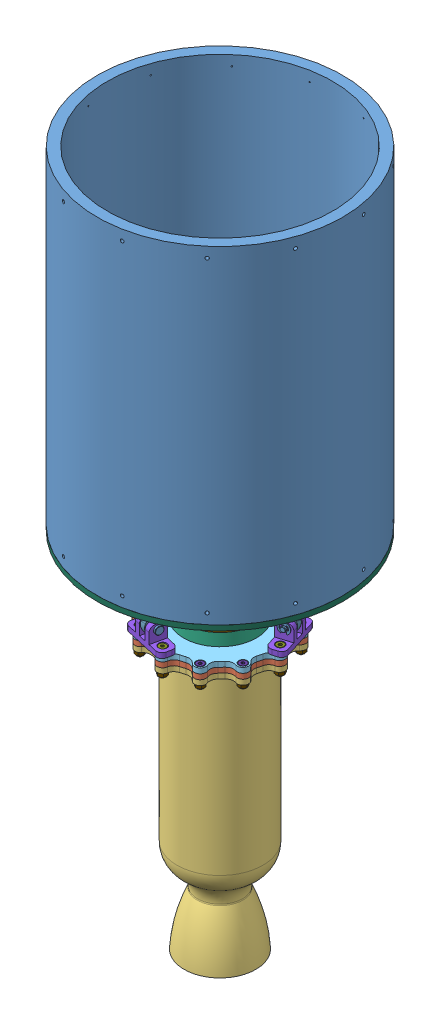
SolidWorks assembly 000067-R01_ENGINE_ASSM, configuration Default. Lengths in mm.
Overall size (591.83 861.8 591.83).
60 component instances, 19 part files, 17 mates.
Components (placement in the parent):
- 000057-R01_FIN_CAN_TUBE_ASSM-1: 000057-R01_FIN_CAN_TUBE_ASSM [Default] at (22.2086 29.6908 -254.9462) x (0.98247 0 -0.186422) z (0.186422 0 0.98247) size (304.8 406.4 304.8)
  - 000070-R01_FIN_CAN_AF-1: 000070-R01_FIN_CAN_AF [Default] at (6.0261 200.1811 396.9011) size (304.8 406.4 304.8)
- 000014-R02_REMOVE_BEFORE_FLIGHT_ASSM-1: 000014-R02_REMOVE_BEFORE_FLIGHT_ASSM [Default] at (94.6044 -143.2219 138.4138) x (-0.855947 0 0.517064) z (-0.517064 0 -0.855947) size (431.04 487.19 431.04)
  - 000030-R02_FILM_COOLING_VOLUTE-2: 000030-R02_FILM_COOLING_VOLUTE [Default] at (-8.7806 254.8412 0) x (-0.965926 0 -0.258819) z (0.258819 0 -0.965926) size (156.79 34.88 257.08)
  - 000001-R05_RBF_TCA-2: 000001-R05_RBF_TCA [Default] at (-8.7806 -14.701 0) x (0 -1 0) z (0 0 1) size (343.5 185.64 158.75)
  - 000015-R05_PINTLE_INJECT_ASSM-1: 000015-R05_PINTLE_INJECT_ASSM [Default] at (86.4435 164.1172 71.5928) x (-0.866025 0 0.5) z (-0.5 0 -0.866025) size (158.75 36.86 158.75)
    - 000033-R01_PINTLE_BOTTOM_PLATE-1: 000033-R01_PINTLE_BOTTOM_PLATE [Default] at (46.67 88.1839 109.6132) size (87.7 15.24 87.7)
    - 000032-R02_PINTLE_MIDDLE_PLATE-1: 000032-R02_PINTLE_MIDDLE_PLATE [Default] at (46.67 92.7382 109.6132) size (158.75 29.57 158.75)
    - 000031-R01_PINTLE_UPPER_PLATE-1: 000031-R01_PINTLE_UPPER_PLATE [Default] at (46.67 125.0393 109.6132) size (90.17 15.27 90.17)
    - MISUMI_MSBH6-20-1: MISUMI_MSBH6-20 [Default] at (8.57 121.0393 109.6132) x (0 -1 0) z (0 0 1) size (31 9 9)
  - engine-side-clevis-1: engine-side-clevis [Default] at (-7.5695 273.8912 0.6838) x (0.693392 0 -0.72056) z (0.72056 0 0.693392) size (19.05 25.4 57.15)
  - 000012_R04_ASI_ASSEM-1: 000012_R04_ASI_ASSEM [Default] at (-8.7806 251.1654 0) x (-0.959573 0 0.281459) z (-0.281459 0 -0.959573) size (117.68 93.77 117.68)
    - 000011-R02_ASI_TOP-1: 000011-R02_ASI_TOP [Default] at (0 37.9912 0) x (-0.924896 0 -0.380219) z (0.380219 0 -0.924896) size (90.17 60.14 90.17)
    - 000011-R02_ASI_BOTTOM-1: 000011-R02_ASI_BOTTOM [Default] at (0 4.4632 0) x (0.915191 0 -0.40302) z (0.40302 0 0.915191) size (30.48 24.13 30.48)
    - 000010-R02_ASI-1: 000010-R02_ASI [Default] at (0 63.3912 0) x (-0.133168 0 -0.991093) z (0.991093 0 -0.133168) size (45.72 18.88 45.72)
  - 000061-R01_THRUST_MOUNT_ASSM-6: 000061-R01_THRUST_MOUNT_ASSM [Default] at (108.3978 328.6699 -153.5919) x (-0.197262 0.979436 -0.042345) z (0.576802 0.15088 0.802829) size (118.32 96.83 60.51) (flexible)
    - 000029-R01_LAUNCH_MOUNT_CLEVIS-1: 000029-R01_LAUNCH_MOUNT_CLEVIS [Default] at (58.7034 52.1122 43.2404) x (0.980239 -0.133241 0.146211) z (-0.165429 -0.146887 0.975222) size (31.75 38.1 50.8)
    - THREADED_ROD-1: THREADED_ROD [Default] at (36.9792 86.6959 44.7642) x (0.299604 0.419939 -0.856673) z (0.366938 0.778134 0.509768) size (12.7 50.8 12.7)
    - 8405K111_THRUST-RATED BALL JOINT ROD END-1: 8405K111_THRUST-RATED BALL JOINT ROD END [8405K111] at (-12.0929 112.7217 40.36) x (0.441581 0.869836 0.219984) z (-0.171501 -0.158832 0.972296) size (19.88 46.6 9.53)
    - 8405K111_THRUST-RATED BALL JOINT ROD END-2: 8405K111_THRUST-RATED BALL JOINT ROD END [8405K111] at (47.1332 81.3106 45.6756) x (-0.443891 -0.871932 -0.206628) z (-0.165429 -0.146887 0.975222) size (19.88 46.6 9.53)
  - engine-side-clevis-6: engine-side-clevis [Default] at (-9.9782 273.8912 0.7069) x (0.277328 0 0.960775) z (-0.960775 0 0.277328) size (19.05 25.4 57.15)
  - engine-side-clevis-7: engine-side-clevis [Default] at (-8.7939 273.8912 -1.3907) x (-0.97072 0 -0.240215) z (0.240215 0 -0.97072) size (19.05 25.4 57.15)
  - 000061-R01_THRUST_MOUNT_ASSM-7: 000061-R01_THRUST_MOUNT_ASSM [Default] at (65.6447 328.6699 178.2754) x (0.135303 0.979436 -0.149661) z (-0.983671 0.15088 0.098111) size (118.32 96.83 60.51) (flexible)
    - 000029-R01_LAUNCH_MOUNT_CLEVIS-1: 000029-R01_LAUNCH_MOUNT_CLEVIS [Default] at (58.7034 52.1122 43.2404) x (0.980239 -0.133241 0.146211) z (-0.165429 -0.146887 0.975222) size (31.75 38.1 50.8)
    - THREADED_ROD-1: THREADED_ROD [Default] at (36.7589 86.8127 44.7445) x (0.039613 0.238881 0.97024) z (-0.472056 -0.851338 0.22888) size (12.7 50.8 12.7)
    - 8405K111_THRUST-RATED BALL JOINT ROD END-1: 8405K111_THRUST-RATED BALL JOINT ROD END [8405K111] at (-12.0929 112.7217 40.36) x (0.441581 0.869836 0.219984) z (-0.171501 -0.158832 0.972296) size (19.88 46.6 9.53)
    - 8405K111_THRUST-RATED BALL JOINT ROD END-2: 8405K111_THRUST-RATED BALL JOINT ROD END [8405K111] at (47.1332 81.3106 45.6756) x (-0.443891 -0.871932 -0.206628) z (-0.165429 -0.146887 0.975222) size (19.88 46.6 9.53)
  - 000061-R01_THRUST_MOUNT_ASSM-8: 000061-R01_THRUST_MOUNT_ASSM [Default] at (-200.3842 328.6699 -24.6835) x (0.061959 0.979436 0.192007) z (0.406869 0.15088 -0.90094) size (124.54 97.67 60.51) (flexible)
    - 000029-R01_LAUNCH_MOUNT_CLEVIS-1: 000029-R01_LAUNCH_MOUNT_CLEVIS [Default] at (58.7034 52.1122 43.2404) x (-0.980239 0.133241 -0.146211) z (0.165429 0.146887 -0.975222) size (31.75 38.1 50.8)
    - THREADED_ROD-1: THREADED_ROD [Default] at (36.7628 86.8107 44.7448) x (0.181458 0.17849 -0.967065) z (0.437583 0.866015 0.241947) size (12.7 50.8 12.7)
    - 8405K111_THRUST-RATED BALL JOINT ROD END-1: 8405K111_THRUST-RATED BALL JOINT ROD END [8405K111] at (-12.0929 112.7217 40.36) x (0.441581 0.869836 0.219984) z (-0.171501 -0.158832 0.972296) size (19.88 46.6 9.53)
    - 8405K111_THRUST-RATED BALL JOINT ROD END-2: 8405K111_THRUST-RATED BALL JOINT ROD END [8405K111] at (47.1332 81.3106 45.6756) x (0.443891 0.871932 0.206628) z (0.165429 0.146887 -0.975222) size (19.88 46.6 9.53)
  - 000066-R01_THRUST_MOUNT-1: 000066-R01_THRUST_MOUNT [Default] at (-8.7806 366.7438 0) x (0.702595 0 -0.71159) z (0.71159 0 0.702595) size (304.8 38.1 304.8)
- 97381A304_ALUMINUM SHOULDER SCREW-1: 97381A304_ALUMINUM SHOULDER SCREW [97381A304] at (175.1854 137.0066 132.2325) x (-0.998361 0 -0.057233) z (0 1 0) size (9.53 9.53 33.96)
- 97381A303_ALUMINUM SHOULDER SCREW-1: 97381A303_ALUMINUM SHOULDER SCREW [97381A303] at (40.1581 130.6566 171.3039) x (1 0 0) z (0 1 0) size (9.53 9.53 27.61)
- 97381A303_ALUMINUM SHOULDER SCREW-2: 97381A303_ALUMINUM SHOULDER SCREW [97381A303] at (165.5166 130.6566 168.8192) x (-0.5 0 -0.866025) z (0 1 0) size (9.53 9.53 27.61)
- 97381A303_ALUMINUM SHOULDER SCREW-3: 97381A303_ALUMINUM SHOULDER SCREW [97381A303] at (139.5503 130.6566 195.8357) x (0 0 -1) z (0 1 0) size (9.53 9.53 27.61)
- 97381A303_ALUMINUM SHOULDER SCREW-4: 97381A303_ALUMINUM SHOULDER SCREW [97381A303] at (137.0656 130.6566 70.4772) x (-0.866025 0 0.5) z (0 1 0) size (9.53 9.53 27.61)
- 97381A303_ALUMINUM SHOULDER SCREW-5: 97381A303_ALUMINUM SHOULDER SCREW [97381A303] at (29.7443 130.6566 135.3082) x (0.866025 0 0.5) z (0 1 0) size (9.53 9.53 27.61)
- 97381A303_ALUMINUM SHOULDER SCREW-6: 97381A303_ALUMINUM SHOULDER SCREW [97381A303] at (100.6855 130.6566 61.4979) x (-0.5 0 0.866025) z (0 1 0) size (9.53 9.53 27.61)
- 97381A304_ALUMINUM SHOULDER SCREW-3: 97381A304_ALUMINUM SHOULDER SCREW [97381A304] at (103.7613 137.0066 206.9391) x (0.057233 0 -0.998361) z (0 1 0) size (9.53 9.53 33.96)
- 97381A304_ALUMINUM SHOULDER SCREW-4: 97381A304_ALUMINUM SHOULDER SCREW [97381A304] at (67.0087 137.0066 197.9708) x (0.548745 0 -0.83599) z (0 1 0) size (9.53 9.53 33.96)
- 97381A304_ALUMINUM SHOULDER SCREW-5: 97381A304_ALUMINUM SHOULDER SCREW [97381A304] at (38.023 137.0066 98.7624) x (0.83599 0 0.548745) z (0 1 0) size (9.53 9.53 33.96)
- 97381A304_ALUMINUM SHOULDER SCREW-6: 97381A304_ALUMINUM SHOULDER SCREW [97381A304] at (64.166 137.0066 71.4179) x (0.449616 0 0.893222) z (0 1 0) size (9.53 9.53 33.96)
- 97381A304_ALUMINUM SHOULDER SCREW-7: 97381A304_ALUMINUM SHOULDER SCREW [97381A304] at (164.5759 137.0066 95.9196) x (-0.893222 0 0.449616) z (0 1 0) size (9.53 9.53 33.96)
- 95856A225_ALUMINUM NYLON-INSERT LOCKNUT-1: 95856A225_ALUMINUM NYLON-INSERT LOCKNUT [95856A225] at (40.1581 111.6193 171.3039) x (-0.837169 0 -0.546944) z (-0.546944 0 0.837169) size (9.53 6.11 11)
- 95856A225_ALUMINUM NYLON-INSERT LOCKNUT-2: 95856A225_ALUMINUM NYLON-INSERT LOCKNUT [95856A225] at (165.5166 111.6193 168.8192) x (-0.055083 0 0.998482) z (0.998482 0 0.055083) size (9.53 6.11 11)
- 95856A225_ALUMINUM NYLON-INSERT LOCKNUT-3: 95856A225_ALUMINUM NYLON-INSERT LOCKNUT [95856A225] at (139.5503 111.6193 195.8357) x (-0.546944 0 0.837169) z (0.837169 0 0.546944) size (9.53 6.11 11)
- 95856A225_ALUMINUM NYLON-INSERT LOCKNUT-4: 95856A225_ALUMINUM NYLON-INSERT LOCKNUT [95856A225] at (137.0656 111.6193 70.4772) x (0.998482 0 0.055083) z (0.055083 0 -0.998482) size (9.53 6.11 11)
- 95856A225_ALUMINUM NYLON-INSERT LOCKNUT-5: 95856A225_ALUMINUM NYLON-INSERT LOCKNUT [95856A225] at (29.7443 111.6193 135.3082) x (-0.451538 0 -0.892252) z (-0.892252 0 0.451538) size (9.53 6.11 11)
- 95856A225_ALUMINUM NYLON-INSERT LOCKNUT-6: 95856A225_ALUMINUM NYLON-INSERT LOCKNUT [95856A225] at (100.6855 111.6193 61.4979) x (0.892252 0 -0.451538) z (-0.451538 0 -0.892252) size (9.53 6.11 11)
- 95856A225_ALUMINUM NYLON-INSERT LOCKNUT-7: 95856A225_ALUMINUM NYLON-INSERT LOCKNUT [95856A225] at (175.1854 111.6193 132.2325) x (-0.837169 0 -0.546944) z (-0.546944 0 0.837169) size (9.53 6.11 11)
- 95856A225_ALUMINUM NYLON-INSERT LOCKNUT-8: 95856A225_ALUMINUM NYLON-INSERT LOCKNUT [95856A225] at (103.7613 111.6193 206.9391) x (0.546944 0 -0.837169) z (-0.837169 0 -0.546944) size (9.53 6.11 11)
- 95856A225_ALUMINUM NYLON-INSERT LOCKNUT-9: 95856A225_ALUMINUM NYLON-INSERT LOCKNUT [95856A225] at (67.0087 111.6193 197.9708) x (0.892252 0 -0.451538) z (-0.451538 0 -0.892252) size (9.53 6.11 11)
- 95856A225_ALUMINUM NYLON-INSERT LOCKNUT-10: 95856A225_ALUMINUM NYLON-INSERT LOCKNUT [95856A225] at (38.023 111.6193 98.7624) x (0.451538 0 0.892252) z (0.892252 0 -0.451538) size (9.53 6.11 11)
- 95856A225_ALUMINUM NYLON-INSERT LOCKNUT-11: 95856A225_ALUMINUM NYLON-INSERT LOCKNUT [95856A225] at (64.166 111.6193 71.4179) x (-0.055083 0 0.998482) z (0.998482 0 0.055083) size (9.53 6.11 11)
- 95856A225_ALUMINUM NYLON-INSERT LOCKNUT-12: 95856A225_ALUMINUM NYLON-INSERT LOCKNUT [95856A225] at (164.5759 111.6193 95.9196) x (-0.998482 0 -0.055083) z (-0.055083 0 0.998482) size (9.53 6.11 11)
- MCMASTER_92735A230_GROOVED CLEVIS PIN WITH RETAINING RING-1: MCMASTER_92735A230_GROOVED CLEVIS PIN WITH RETAINING RING [92735A230] at (52.5765 149.7193 84.0573) x (0.73416 0 0.678977) z (-0.678977 0 0.73416) size (13.39 13.39 27.94)
- MCMASTER_92735A230_GROOVED CLEVIS PIN WITH RETAINING RING-3: MCMASTER_92735A230_GROOVED CLEVIS PIN WITH RETAINING RING [92735A230] at (170.0341 149.7193 115.8759) x (-0.955091 0 0.296313) z (-0.296313 0 -0.955091) size (13.39 13.39 27.94)
- MCMASTER_92735A230_GROOVED CLEVIS PIN WITH RETAINING RING-4: MCMASTER_92735A230_GROOVED CLEVIS PIN WITH RETAINING RING [92735A230] at (83.7496 149.7193 201.6879) x (0.173041 0.621726 -0.763881) z (0.975289 0 0.220931) size (13.39 13.39 27.94)
Mates (geometry in assembly coordinates):
- Concentric1: concentric anti-aligned: cylinder of 000057-R01_FIN_CAN_TUBE_ASSM-1/000070-R01_FIN_CAN_AF-1 through (102.1201 636.2719 133.8737) axis (0 -1 0) radius 139.7; cylinder of 000014-R02_REMOVE_BEFORE_FLIGHT_ASSM-1/000001-R05_RBF_TCA-2 through (102.1201 78.5517 133.8737) axis (0 1 0) radius 53.373
- Concentric3: concentric anti-aligned: cylinder of 000057-R01_FIN_CAN_TUBE_ASSM-1/000070-R01_FIN_CAN_AF-1 through (102.1201 636.2719 133.8737) axis (0 -1 0) radius 152.4; cylinder of 000014-R02_REMOVE_BEFORE_FLIGHT_ASSM-1/000066-R01_THRUST_MOUNT-1 through (102.1201 229.8719 133.8737) axis (0 1 0) radius 139.7
- Coincident7: coincident aligned: circle of 000057-R01_FIN_CAN_TUBE_ASSM-1/000070-R01_FIN_CAN_AF-1; plane of 000014-R02_REMOVE_BEFORE_FLIGHT_ASSM-1/000066-R01_THRUST_MOUNT-1 through (102.1201 229.8719 133.8737) normal (0 1 0)
- Concentric6: concentric aligned: cylinder of 000014-R02_REMOVE_BEFORE_FLIGHT_ASSM-1/000015-R05_PINTLE_INJECT_ASSM-1/000032-R02_PINTLE_MIDDLE_PLATE-1 through (40.1581 130.6693 171.3039) axis (0 -1 0) radius 5.1587; cylinder of 97381A303_ALUMINUM SHOULDER SCREW-1 through (40.1581 103.6691 171.3039) axis (0 -1 0) radius 3.175
- Coincident11: coincident anti-aligned: plane of 000014-R02_REMOVE_BEFORE_FLIGHT_ASSM-1/000015-R05_PINTLE_INJECT_ASSM-1/000032-R02_PINTLE_MIDDLE_PLATE-1 through (41.7889 125.8941 168.3454) normal (0 1 0); plane of 97381A303_ALUMINUM SHOULDER SCREW-1 through (40.1581 125.8941 176.0664) normal (0 -1 0)
- Coincident15: coincident anti-aligned: plane of 000014-R02_REMOVE_BEFORE_FLIGHT_ASSM-1/engine-side-clevis-7 through (178.4119 132.2441 131.2314) normal (0 1 0); plane of 97381A304_ALUMINUM SHOULDER SCREW-1 through (175.458 132.2441 127.4778) normal (0 -1 0)
- Concentric9: concentric anti-aligned: cylinder of 000014-R02_REMOVE_BEFORE_FLIGHT_ASSM-1/engine-side-clevis-7 through (175.1854 137.0193 132.2325) axis (0 1 0) radius 5.1587; cylinder of 97381A304_ALUMINUM SHOULDER SCREW-1 through (175.1854 103.6691 132.2325) axis (0 -1 0) radius 3.175
- Coincident17: coincident anti-aligned: plane of 000014-R02_REMOVE_BEFORE_FLIGHT_ASSM-1/000001-R05_RBF_TCA-2 through (56.4356 111.6193 161.471) normal (0 -1 0); plane of 95856A225_ALUMINUM NYLON-INSERT LOCKNUT-1 through (32.184 111.6193 166.0943) normal (0 1 0)
- Concentric11: concentric anti-aligned: circle of 97381A303_ALUMINUM SHOULDER SCREW-1; circle of 95856A225_ALUMINUM NYLON-INSERT LOCKNUT-1
- Coincident18: coincident anti-aligned: plane of 000014-R02_REMOVE_BEFORE_FLIGHT_ASSM-1/000001-R05_RBF_TCA-2 through (56.4356 111.6193 161.471) normal (0 -1 0); plane of 95856A225_ALUMINUM NYLON-INSERT LOCKNUT-7 through (167.2114 111.6193 127.0228) normal (0 1 0)
- Concentric13: concentric anti-aligned: circle of 97381A304_ALUMINUM SHOULDER SCREW-1; circle of 95856A225_ALUMINUM NYLON-INSERT LOCKNUT-7
- Concentric14: concentric aligned: cylinder of 000014-R02_REMOVE_BEFORE_FLIGHT_ASSM-1/engine-side-clevis-6 through (32.0969 149.7193 106.2014) axis (0.678977 0 -0.73416) radius 3.175; cylinder of MCMASTER_92735A230_GROOVED CLEVIS PIN WITH RETAINING RING-1 through (43.9535 149.7193 93.3812) axis (0.678977 0 -0.73416) radius 3.175
- Coincident19: coincident anti-aligned: plane of 000014-R02_REMOVE_BEFORE_FLIGHT_ASSM-1/engine-side-clevis-6 through (50.9464 156.0693 99.8484) normal (-0.678977 0 0.73416); plane of MCMASTER_92735A230_GROOVED CLEVIS PIN WITH RETAINING RING-1 through (43.9535 149.7193 93.3812) normal (0.678977 0 -0.73416)
- Concentric16: concentric aligned: cylinder of 000014-R02_REMOVE_BEFORE_FLIGHT_ASSM-1/engine-side-clevis-1 through (113.1668 149.7193 208.3517) axis (-0.975289 0 -0.220931) radius 3.175; cylinder of MCMASTER_92735A230_GROOVED CLEVIS PIN WITH RETAINING RING-4 through (96.1358 149.7193 204.4937) axis (-0.975289 0 -0.220931) radius 3.175
- Coincident20: coincident anti-aligned: plane of 000014-R02_REMOVE_BEFORE_FLIGHT_ASSM-1/engine-side-clevis-1 through (98.2402 156.0693 195.204) normal (0.975289 0 0.220931); plane of MCMASTER_92735A230_GROOVED CLEVIS PIN WITH RETAINING RING-4 through (96.1358 149.7193 204.4937) normal (-0.975289 0 -0.220931)
- Concentric17: concentric aligned: cylinder of 000014-R02_REMOVE_BEFORE_FLIGHT_ASSM-1/engine-side-clevis-7 through (161.0965 149.7193 87.068) axis (0.296313 0 0.955091) radius 3.175; cylinder of MCMASTER_92735A230_GROOVED CLEVIS PIN WITH RETAINING RING-3 through (166.2709 149.7193 103.7462) axis (0.296313 0 0.955091) radius 3.175
- Coincident21: coincident anti-aligned: plane of 000014-R02_REMOVE_BEFORE_FLIGHT_ASSM-1/engine-side-clevis-7 through (157.1737 156.0693 106.5686) normal (-0.296313 0 -0.955091); plane of MCMASTER_92735A230_GROOVED CLEVIS PIN WITH RETAINING RING-3 through (166.2709 149.7193 103.7462) normal (0.296313 0 0.955091)
